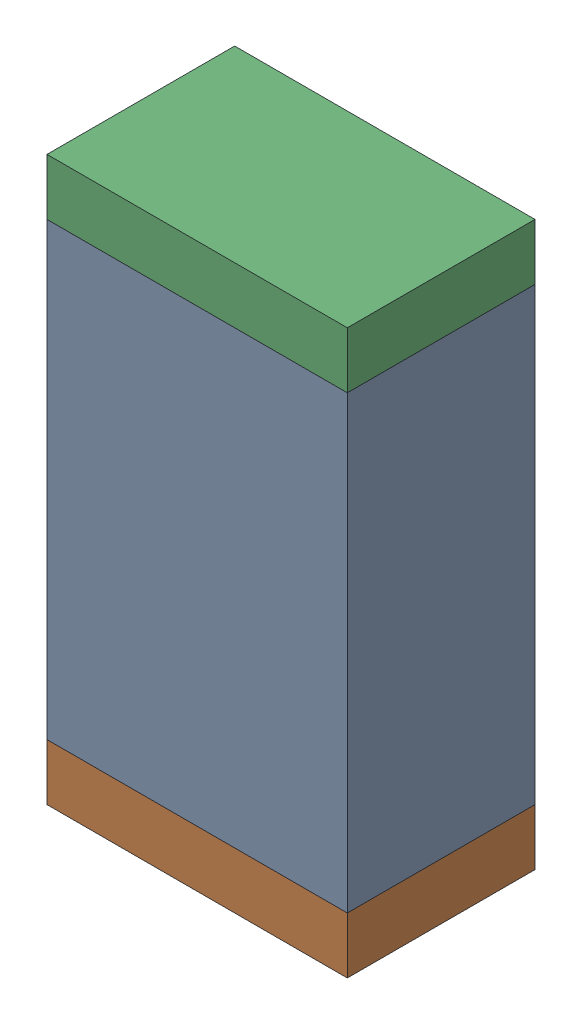
SolidWorks assembly L9, configuration Default. Lengths in mm.
Overall size (0.8 1.5 0.5).
6 component instances, 2 part files, 0 mates.
Components (placement in the parent):
- 810156976-1: 810156976 [Default] at (133.05 46.9 0) size (0.8 1.2 0.5)
  - Extruded_6-1: Extruded_6 [Default] at origin size (0.8 1.2 0.5)
- 810156592-1: 810156592 [Default] at (133.05 46.225 0) size (0.8 0.15 0.5)
  - Extruded_7-1: Extruded_7 [Default] at origin size (0.8 0.15 0.5)
- 810156592-2: 810156592 [Default] at (133.05 47.575 0) size (0.8 0.15 0.5)
  - Extruded_7-1: Extruded_7 [Default] at origin size (0.8 0.15 0.5)
